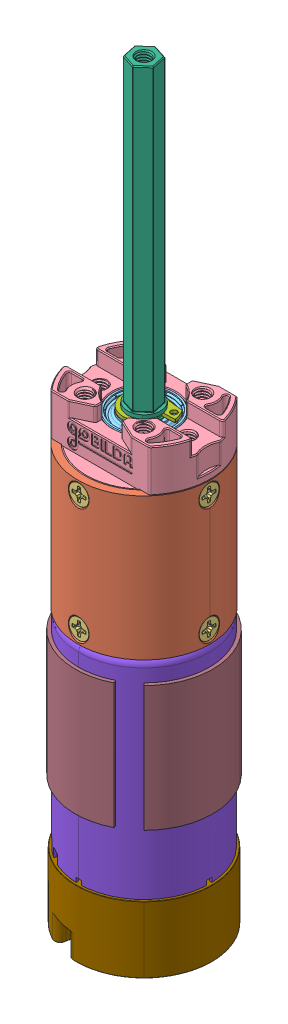
SolidWorks assembly 5204-8002-0071 assembly, configuration Default. Lengths in mm.
Overall size (52.29 204.75 52.29).
30 component instances, 15 part files, 0 mates.
Components (placement in the parent):
- 5204-8002-0071 assembly.STEP-1: 5204-8002-0071 assembly.STEP [Default] at origin size (52.29 204.75 52.29)
  - 5104-8002-0071 Simple.STEP-1: 5104-8002-0071 Simple.STEP [Default] at (21.5499 39.1 -25.8711) size (36 129.8 35.97)
    - 5103 Gearbox Base.STEP-1: 5103 Gearbox Base.STEP [Default] at (-58.7206 21.0354 14.7927) size (31.91 5.69 31.91)
    - 5103 Gearbox Barrel (3 stage, simple)_Gear Blank.STEP-1: 5103 Gearbox Barrel (3 stage, simple)_Gear Blank.STEP [Default] at (-58.7206 72.7354 14.7927) x (1 0 0) z (0 -1 0) size (35.97 35.97 38.7)
    - 5103 Gearbox Barrel Screw (M3 x 8mm length Flat Head)_92010A118.STEP-1: 5103 Gearbox Barrel Screw (M3 x 8mm length Flat Head)_92010A118.STEP [Default] at (-58.7206 24.5354 30.8757) x (0.002439 -0.999997 0) z (0 0 1) size (5.46 5.46 8)
    - 5103 Gearbox Barrel Screw (M3 x 8mm length Flat Head)_92010A118.STEP-2: 5103 Gearbox Barrel Screw (M3 x 8mm length Flat Head)_92010A118.STEP [Default] at (-58.7206 56.2354 30.8757) x (-0.002439 -0.999997 0) z (0 0 1) size (5.46 5.46 8)
    - 5103 Gearbox Barrel Screw (M3 x 8mm length Flat Head)_92010A118.STEP-3: 5103 Gearbox Barrel Screw (M3 x 8mm length Flat Head)_92010A118.STEP [Default] at (-42.6376 24.5354 14.7927) x (0 -0.999997 -0.002439) z (1 0 0) size (5.46 5.46 8)
    - 5103 Gearbox Barrel Screw (M3 x 8mm length Flat Head)_92010A118.STEP-4: 5103 Gearbox Barrel Screw (M3 x 8mm length Flat Head)_92010A118.STEP [Default] at (-58.7206 24.5354 -1.2903) x (-0.002439 -0.999997 0) z (0 0 -1) size (5.46 5.46 8)
    - 5103 Gearbox Barrel Screw (M3 x 8mm length Flat Head)_92010A118.STEP-5: 5103 Gearbox Barrel Screw (M3 x 8mm length Flat Head)_92010A118.STEP [Default] at (-74.8037 24.5354 14.7927) x (0 -0.999997 0.002439) z (-1 0 0) size (5.46 5.46 8)
    - 5103 Gearbox Barrel Screw (M3 x 8mm length Flat Head)_92010A118.STEP-6: 5103 Gearbox Barrel Screw (M3 x 8mm length Flat Head)_92010A118.STEP [Default] at (-42.6376 56.2354 14.7927) x (0 -0.999997 0.002439) z (1 0 0) size (5.46 5.46 8)
    - 5103 Gearbox Barrel Screw (M3 x 8mm length Flat Head)_92010A118.STEP-7: 5103 Gearbox Barrel Screw (M3 x 8mm length Flat Head)_92010A118.STEP [Default] at (-58.7206 56.2354 -1.2903) x (0.002439 -0.999997 0) z (0 0 -1) size (5.46 5.46 8)
    - 5103 Gearbox Barrel Screw (M3 x 8mm length Flat Head)_92010A118.STEP-8: 5103 Gearbox Barrel Screw (M3 x 8mm length Flat Head)_92010A118.STEP [Default] at (-74.8037 56.2354 14.7927) x (0 -0.999997 -0.002439) z (-1 0 0) size (5.46 5.46 8)
    - 5103 Gearbox Face.STEP-1: 5103 Gearbox Face.STEP [Default] at (-58.7206 54.2354 14.7927) size (36 17.1 31.91)
    - 5103 Gearbox Bearing.STEP-1: 5103 Gearbox Bearing.STEP [Default] at (-58.7206 62.3354 14.7927) size (17 5 17)
    - 5103 Gearbox Bearing.STEP-2: 5103 Gearbox Bearing.STEP [Default] at (-58.7206 54.2354 14.7927) size (17 5 17)
    - 5103 Gearbox Shaft (79.5mm Length, Simple).STEP-1: 5103 Gearbox Shaft (79.5mm Length, Simple).STEP [Default] at (-58.7206 50.8754 14.7927) x (0.74423 0 -0.667923) z (0.667923 0 0.74423) size (8.97 96.6 8.97)
    - 5103 Gearbox Snap Ring.STEP-1: 5103 Gearbox Snap Ring.STEP [Default] at (-58.7206 67.4104 14.7927) x (0 1 0) z (0 0 1) size (0.85 13.06 10.66)
  - 5000-0002-0001 body.STEP-1: 5000-0002-0001 body.STEP [Default] at (-37.1707 3.4854 -11.0784) size (35.61 61.45 35.61)
  - 5000-0001-0001 encoder cap.STEP-1: 5000-0001-0001 encoder cap.STEP [Default] at (-37.1707 -14.6146 -11.0784) x (0.707107 0 -0.707107) z (0 -1 0) size (36.9 36.9 18.3)
  - 5000-0001-0001 encoder cap screw_90190A075.STEP-1: 5000-0001-0001 encoder cap screw_90190A075.STEP [Default] at (-33.0775 -8.1646 -26.1474) x (0.882398 0 0.470504) z (0 -1 0) size (3.33 3.33 7.86)
  - 5000-0001-0001 encoder pin housing.STEP-1: 5000-0001-0001 encoder pin housing.STEP [Default] at (-44.0085 -0.9746 -21.9467) x (0.707107 0 -0.707107) z (-0.707107 0 -0.707107) size (12.3 7.19 6.3)
  - 5000-0001-0001 encoder pins_MalePinHeader_1X2.STEP-1: 5000-0001-0001 encoder pins_MalePinHeader_1X2.STEP [Default] at (-43.4569 1.2544 -23.1912) x (0.707107 0 -0.707107) z (0 -1 0) size (3.18 0.64 4.27)
  - 5000-0001-0001 motor shield.STEP-1: 5000-0001-0001 motor shield.STEP [Default] at (-37.1707 54.6354 -11.0784) x (0.808104 0 -0.58904) z (0 -1 0) size (37.5 37.27 34.15)
  - 5000-0001-0001 encoder cap screw_90190A075.STEP-2: 5000-0001-0001 encoder cap screw_90190A075.STEP [Default] at (-41.264 -8.1646 3.9905) x (0.882398 0 0.470504) z (0 -1 0) size (3.33 3.33 7.86)
  - 5000-0001-0001 encoder pins_MalePinHeader_1X2.STEP-2: 5000-0001-0001 encoder pins_MalePinHeader_1X2.STEP [Default] at (-47.049 1.2544 -19.5991) x (0.707107 0 -0.707107) z (0 -1 0) size (3.18 0.64 4.27)
  - 5000-0002-0117 motor shaft.STEP-1: 5000-0002-0117 motor shaft.STEP [Default] at (-37.1707 59.4854 -11.0784) size (3.26 12.45 3.14)
  - 5103 Gearbox Base Mounting Screw M3 x 5mm length SHCS)_91290A110.STEP-1: 5103 Gearbox Base Mounting Screw M3 x 5mm length SHCS)_91290A110.STEP [Default] at (-46.0096 57.2554 -2.2396) x (0.056382 0 0.998409) z (0 -1 0) size (5.5 5.5 8.01)
  - 5103 Gearbox Base Mounting Screw M3 x 5mm length SHCS)_91290A110.STEP-2: 5103 Gearbox Base Mounting Screw M3 x 5mm length SHCS)_91290A110.STEP [Default] at (-28.3319 57.2554 -2.2396) x (0.998409 0 -0.056382) z (0 -1 0) size (5.5 5.5 8.01)
  - 5103 Gearbox Base Mounting Screw M3 x 5mm length SHCS)_91290A110.STEP-3: 5103 Gearbox Base Mounting Screw M3 x 5mm length SHCS)_91290A110.STEP [Default] at (-28.3319 57.2554 -19.9173) x (-0.056382 0 -0.998409) z (0 -1 0) size (5.5 5.5 8.01)
  - 5103 Gearbox Base Mounting Screw M3 x 5mm length SHCS)_91290A110.STEP-4: 5103 Gearbox Base Mounting Screw M3 x 5mm length SHCS)_91290A110.STEP [Default] at (-46.0096 57.2554 -19.9173) x (-0.998409 0 0.056382) z (0 -1 0) size (5.5 5.5 8.01)
